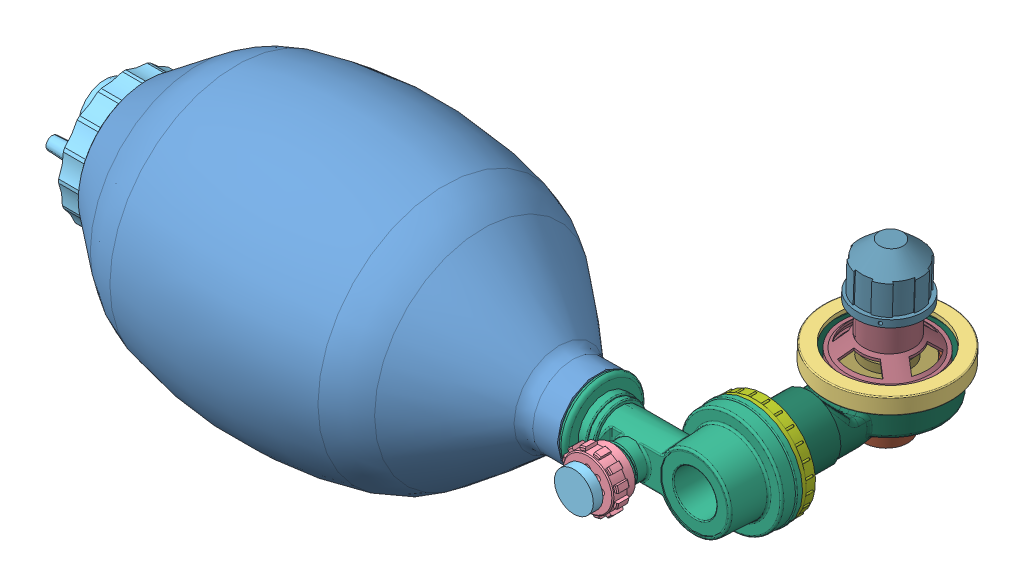
SolidWorks assembly Assy_Ambu-Bag, configuration Default. Lengths in mm.
Overall size (337.54 135.9 184.75).
30 component instances, 26 part files, 11 mates.
Components (placement in the parent):
- Ambu-Bag_Bellows-1: Ambu-Bag_Bellows [Default] at origin size (223 135.9 135.9)
- Assy_Ambu-Bag_Inlet_Inner-1: Assy_Ambu-Bag_Inlet_Inner [Default] at (-85.1284 0 0) x (-1 0 0) z (0 -0.924225 -0.381849) size (17.91 60.3 60.3)
  - Ambu-Bag_Inlet_Inner-1: Ambu-Bag_Inlet_Inner [Default] at origin size (17.56 60.3 60.3)
  - Ambu-Bag_Inlet_Inner_Seal-1: Ambu-Bag_Inlet_Inner_Seal [Default] at (2.65 0 0) x (0 0 -1) z (1 0 0) size (51 51 0.6)
  - Ambu-Bag_Inlet_Inner_Flange-1: Ambu-Bag_Inlet_Inner_Flange [Default] at (-0.35 0 0) size (9 26 26)
- Ambu-Bag_Inlet_Outer_Seal-1: Ambu-Bag_Inlet_Outer_Seal [Default] at (-93.2284 0 0) x (-1 0 0) z (0 -0.173648 0.984808) size (32.91 61.41 61.41)
- Assy_Ambu-Bag_Outlet-1: Assy_Ambu-Bag_Outlet [Default] at (179.2716 0 -14.3) x (0 0 1) z (-1 0 0) size (72.2 65.3 107.95)
  - Ambu-Bag_Outlet-1: Ambu-Bag_Outlet [Default] at origin size (42.06 50.5 100.55)
  - Ambu-Bag_Outlet_Body_Connector-1: Ambu-Bag_Outlet_Body_Connector [Default] x (-1 0 0) z (0 -0.924225 -0.381849) size (13 50 50)
  - Ambu-Bag_Outlet_Body_Connector_Pipe-1: Ambu-Bag_Outlet_Body_Connector_Pipe [Default] at (-36.15 0 0) size (35 30 30)
  - Ambu-Bag_Outlet_Clip-1: Ambu-Bag_Outlet_Clip [Default] at (-13.5 0 0) x (1 0 0) z (0 -0.381849 0.924225) size (5 30.5 30.5)
  - Ambu-Bag_Outlet_Diaphram-1: Ambu-Bag_Outlet_Diaphram [Default] at (2.6 0 0) x (-1 0 0) z (0 -1 0) size (16 43.5 43.5)
- Assy_PEEP_Valve-1: Assy_PEEP_Valve [Default] at (180.4649 34.0142 -85.8) x (0 0 1) z (0.999385 -0.03506 0) size (88 81.5 62)
  - PEEP_Body_Non_Adjustment-1: PEEP_Body_Non_Adjustment [Default] at origin size (42.96 30.67 43.43)
  - PEEP_Valve_Large_Silicone_Seal-1: PEEP_Valve_Large_Silicone_Seal [Default] at (0 27.5851 0) x (-0.776565 0 -0.630038) z (-0.630038 0 0.776565) size (35.2 9.5 35.2)
  - PEEP_Body_Adjustment_Side-1: PEEP_Body_Adjustment_Side [Default] at (0 -8.7149 0) x (0.568746 0 0.822513) z (-0.822513 0 0.568746) size (44.4 38.92 44.4)
  - PEEP_Adjustment_Knob-1: PEEP_Adjustment_Knob [Default] at (0 -1.5149 0) x (-0.563024 0 0.82644) z (0.82644 0 0.563024) size (32.7 26.64 32.7)
  - PEEP_Adapter_Outlet-1: PEEP_Adapter_Outlet [Default] at (0 21.1851 0) size (86.25 30.7 58.5)
  - PEEP_Pin_Center-1: PEEP_Pin_Center [Default] at (0 33.0851 0) x (-0.837169 0 -0.546944) z (-0.546944 0 0.837169) size (5.5 49 5.5)
  - PEEP_Spring_Taper-1: PEEP_Spring_Taper [Default] at (0 -4.3293 0) size (13.06 27.8 13.19)
  - Platic_Float-1: Platic_Float [Default] at (0 -2.6149 0) x (-0.879727 0 -0.475479) z (-0.475479 0 0.879727) size (19.4 5 19.4)
  - PEEP_Spring_Large-1: PEEP_Spring_Large [Default] at (0 23.1492 0) x (0.672466 0 0.740128) z (0.740128 0 -0.672466) size (17.62 25.6 17.62)
  - PEEP_Adapter_Outlet_Inner_Seal-1: PEEP_Adapter_Outlet_Inner_Seal [Default] at (0 33.6851 0) x (-1 0 0) z (0 0 -1) size (34.8 6.5 34.8)
  - PEEP_Adapter_Outlet_Seal-1: PEEP_Adapter_Outlet_Seal [Default] at (0 17.1851 0) x (-1 0 0) z (0 0 -1) size (62 8 62)
- Assy_Pressure_Relief_Valve-1: Assy_Pressure_Relief_Valve [Default] at (149.2716 0 29.4) x (1 0 0) z (0 1 0) size (27.47 35.1 27.47)
  - Pressure Relief Valve Body-1: Pressure Relief Valve Body [Default] at origin size (27.47 12.53 27.47)
  - Pressure Relief Valve Pop_Up-1: Pressure Relief Valve Pop_Up [Default] at (0 -6.6 0) size (18.9 15.2 18.9)
  - Pressure Relief Valve Spring-1: Pressure Relief Valve Spring [Default] at (0 2.3 0) size (10.63 15.06 10.73)
  - Pressure Relief Valve Pin Center-1: Pressure Relief Valve Pin Center [Default] at (0 3.6 0) size (7.5 24.9 5.65)
  - Pressure Relief Valve Seal-1: Pressure Relief Valve Seal [Default] at (0 10.4 0) x (0.927686 0 -0.373362) z (0.373362 0 0.927686) size (12 11 12)
Mates (geometry in assembly coordinates):
- Coincident1: coincident: plane of assembly; circle of assembly; plane of Ambu-Bag_Bellows-1 through (-92.2284 0 -30.5199) normal (1 0 0); circle of Assy_Ambu-Bag_Inlet_Inner-1/Ambu-Bag_Inlet_Inner-1
- Concentric1: concentric: cylinder of assembly; cylinder of assembly; cylinder of Ambu-Bag_Bellows-1 through (0 0 0) axis (-1 0 0) radius 25.5; cylinder of Assy_Ambu-Bag_Inlet_Inner-1/Ambu-Bag_Inlet_Inner-1 through (-85.1284 0 0) axis (1 0 0) radius 24.35
- Coincident2: coincident: plane of assembly; plane of assembly; plane of Ambu-Bag_Bellows-1 through (-95.2284 0 -30.5199) normal (-1 0 0); plane of Ambu-Bag_Inlet_Outer_Seal-1 through (-95.2284 -27.5746 -4.8621) normal (1 0 0)
- Concentric2: concentric: cylinder of assembly; cylinder of assembly; cylinder of Assy_Ambu-Bag_Inlet_Inner-1/Ambu-Bag_Inlet_Inner-1 through (-85.1284 0 0) axis (1 0 0) radius 24.35; cylinder of Ambu-Bag_Inlet_Outer_Seal-1 through (-93.2284 0 0) axis (1 0 0) radius 19.375
- Coincident3: coincident: plane of assembly; plane of assembly; plane of Ambu-Bag_Bellows-1 through (124.7716 0 -19.5) normal (1 0 0); plane of Assy_Ambu-Bag_Outlet-1/Ambu-Bag_Outlet-1 through (124.7716 19.8 0) normal (-1 0 0)
- Concentric3: concentric: cylinder of assembly; cylinder of assembly; cylinder of Ambu-Bag_Bellows-1 through (0 0 0) axis (-1 0 0) radius 14; cylinder of Assy_Ambu-Bag_Outlet-1/Ambu-Bag_Outlet-1 through (179.2716 0 0) axis (1 0 0) radius 13.4921
- Angle1: planar angle = 4.537856 rad: plane of assembly through (0 0 0) normal (0 1 0); plane of Ambu-Bag_Inlet_Outer_Seal-1 through (-93.2284 0 0) normal (0 -0.173648 0.984808); plane of assembly
- Distance1: distance = 1 mm: plane of assembly; plane of assembly; plane of Assy_PEEP_Valve-1/PEEP_Adapter_Outlet-1 through (179.2716 0 -28.8) normal (0 0 1); plane of Assy_Ambu-Bag_Outlet-1/Ambu-Bag_Outlet_Clip-1 through (174.8803 10.6286 -27.8) normal (0 0 -1)
- Concentric4: concentric: circle of assembly; cylinder of assembly; circle of Assy_Ambu-Bag_Outlet-1/Ambu-Bag_Outlet_Body_Connector_Pipe-1; cylinder of Assy_PEEP_Valve-1/PEEP_Adapter_Outlet-1 through (179.2716 0 -48.3) axis (0 0 1) radius 15.35
- Concentric5: concentric: cylinder of assembly; cylinder of assembly; cylinder of Assy_Ambu-Bag_Outlet-1/Ambu-Bag_Outlet-1 through (149.2716 0 -15.3145) axis (0 0 -1) radius 8.4; cylinder of Assy_Pressure_Relief_Valve-1/Pressure Relief Valve Body-1 through (149.2716 0 29.4) axis (0 0 1) radius 11.2
- Distance2: distance = 4 mm: plane of assembly; plane of assembly; plane of Assy_Pressure_Relief_Valve-1/Pressure Relief Valve Body-1 through (160.4716 0 17.4) normal (0 0 -1); plane of Assy_Ambu-Bag_Outlet-1/Ambu-Bag_Outlet-1 through (158.7716 0 21.4) normal (0 0 1)
